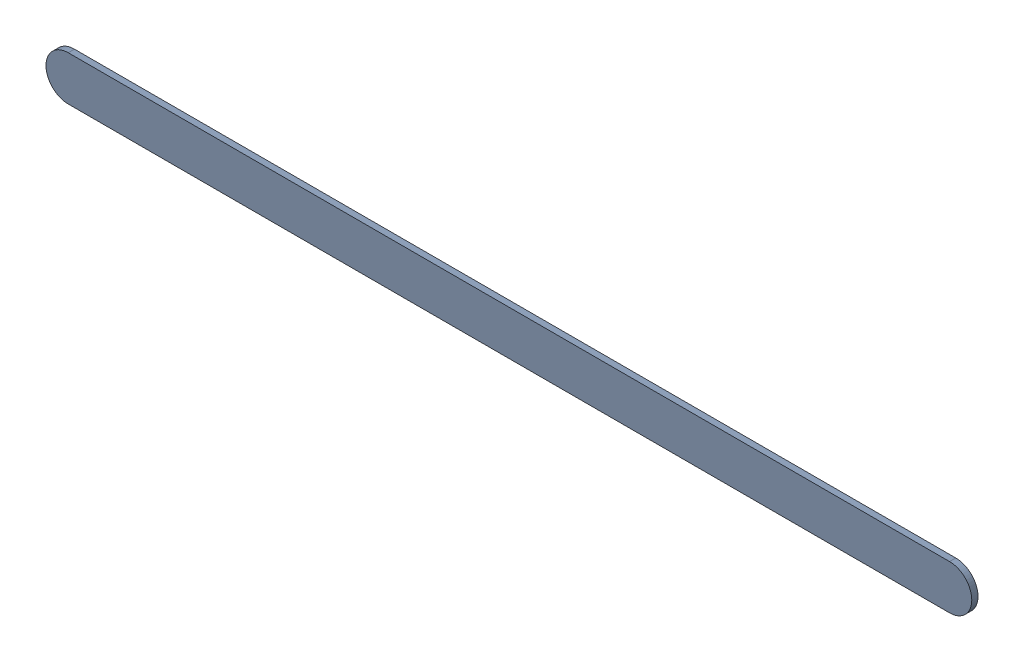
SolidWorks assembly Track (17.356mm,27.093mm)(22.393mm,27.093mm) on Top Layer, configuration Predeterminado. Lengths in mm.
Overall size (5.29 0.25 0.04).
2 component instances, 1 part files, 0 mates.
Components (placement in the parent):
- Track (17.356mm,27.093mm)(22.393mm,27.093mm) on Top Layer-1-1: Track (17.356mm,27.093mm)(22.393mm,27.093mm) on Top Layer-1 [Predeterminado] at (-68.317 -44.187 -0.0457) size (5.29 0.25 0.04)
  - Track (17.356mm,27.093mm)(22.393mm,27.093mm) on Top Layer-Part-1-1: Track (17.356mm,27.093mm)(22.393mm,27.093mm) on Top Layer-Part-1 [Predeterminado] at origin size (5.29 0.25 0.04)
